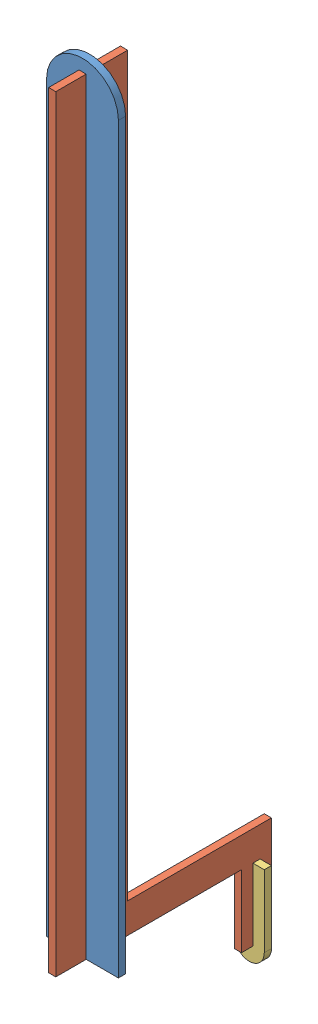
SolidWorks assembly 試做, configuration Default. Lengths in mm.
Overall size (30 361.25 90).
3 component instances, 3 part files, 7 mates.
Components (placement in the parent):
- 主軸桿子1-1: 主軸桿子1 [Default] at (177.5327 28.0042 223.0338) size (30 325 3)
- 主軸桿子2-1: 主軸桿子2 [Default] at (177.5827 33.0042 222.2193) x (0 0 -1) z (1 0 0) size (90 350 3)
- 把手-2: 把手 [Default] at (177.5827 -141.9958 153.4535) x (1 0 0) z (0 0 -1) size (12.5 36.25 3)
Mates (geometry in assembly coordinates):
- Coincident1: coincident anti-aligned: plane of 主軸桿子1-1 through (179.0827 28.0042 224.5338) normal (-1 0 0); plane of 主軸桿子2-1 through (179.0827 33.0042 222.2193) normal (1 0 0)
- Coincident2: coincident anti-aligned: plane of 主軸桿子1-1 through (177.5327 193.0042 224.5338) normal (0 -1 0); plane of 主軸桿子2-1 through (179.0827 193.0042 237.2193) normal (0 1 0)
- Coincident3: coincident aligned: plane of 主軸桿子1-1 through (177.5327 -126.9958 224.5338) normal (0 -1 0); plane of 主軸桿子2-1 through (179.0827 -126.9958 237.2193) normal (0 -1 0)
- Coincident19: coincident anti-aligned: plane of 主軸桿子1-1 through (179.0827 28.0042 224.5338) normal (-1 0 0); plane of 主軸桿子2-1 through (179.0827 33.0042 222.2193) normal (1 0 0)
- Coincident23: coincident anti-aligned: plane of 主軸桿子2-1 through (179.0827 33.0042 222.2193) normal (1 0 0); plane of 把手-2 through (179.0827 -126.9958 151.9535) normal (-1 0 0)
- Coincident24: coincident anti-aligned: plane of 主軸桿子2-1 through (179.0827 -156.9958 159.7193) normal (0 -1 0); plane of 把手-2 through (176.0827 -156.9958 151.9535) normal (0 1 0)
- Coincident25: coincident: plane of 主軸桿子2-1 through (179.0827 -156.9958 159.7193) normal (0 -1 0); line of 把手-2 through (176.0827 -156.9958 154.9535) axis (1 0 0)
